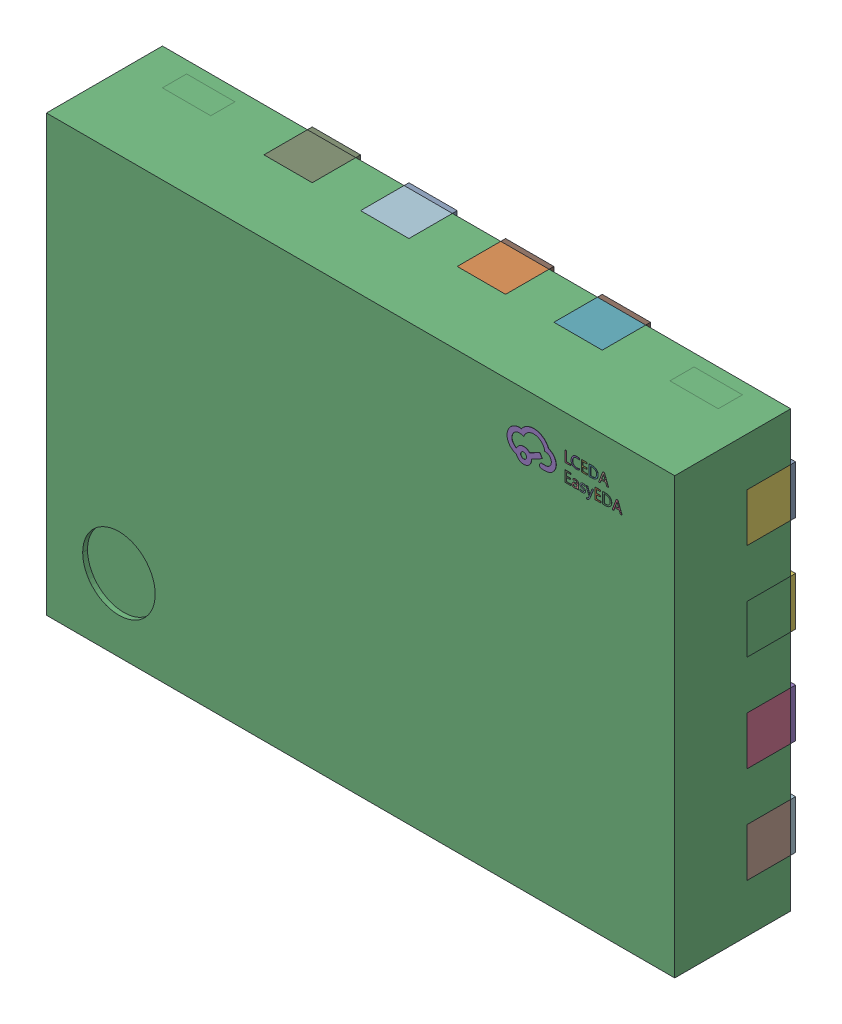
SolidWorks assembly HD3SS3202RSVR, configuration Défaut. Lengths in mm.
Overall size (2.6 1.8 0.5).
3 component instances, 1 part files, 0 mates.
Components (placement in the parent):
- U1.step-1: U1.step [Défaut] at (5.0775 -6.7805 1.6001) size (2.6 1.8 0.5)
  - UQFN-16_L2.6-W1.8-P0.40-BL.step-1: UQFN-16_L2.6-W1.8-P0.40-BL.step [Défaut] at origin size (2.6 1.8 0.5)
    - COMPOUND.step-1: COMPOUND.step [Défaut] at origin size (2.6 1.8 0.5)
